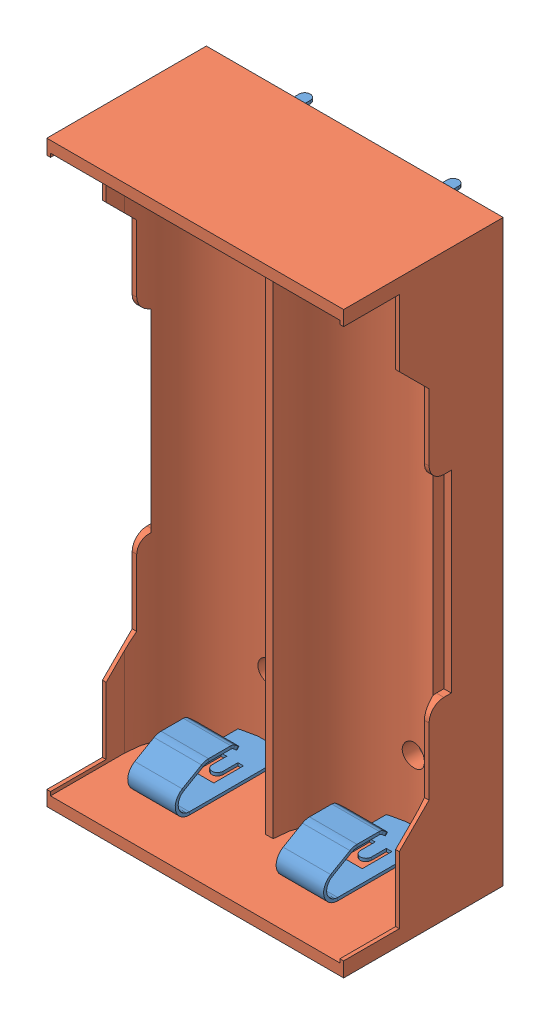
SolidWorks assembly Hold_18650-2p.stp, configuration Default. Lengths in mm.
Overall size (40 78 25.5).
5 component instances, 2 part files, 0 mates.
Components (placement in the parent):
- Hold_18650-2p-prt0.stp-1: Hold_18650-2p-prt0.stp [Default] at (-10 -36 0) size (6.4 5.3 21.4)
- Hold_18650-2p-prt0.stp-2: Hold_18650-2p-prt0.stp [Default] at (-10 36 0) x (-1 0 0) z (0 0 1) size (6.4 5.3 21.4)
- Hold_18650-2p-prt1.stp-1: Hold_18650-2p-prt1.stp [Default] at origin size (40 78 21.5)
- Hold_18650-2p-prt0.stp-3: Hold_18650-2p-prt0.stp [Default] at (10 -36 0) size (6.4 5.3 21.4)
- Hold_18650-2p-prt0.stp-4: Hold_18650-2p-prt0.stp [Default] at (10 36 0) x (-1 0 0) z (0 0 1) size (6.4 5.3 21.4)
